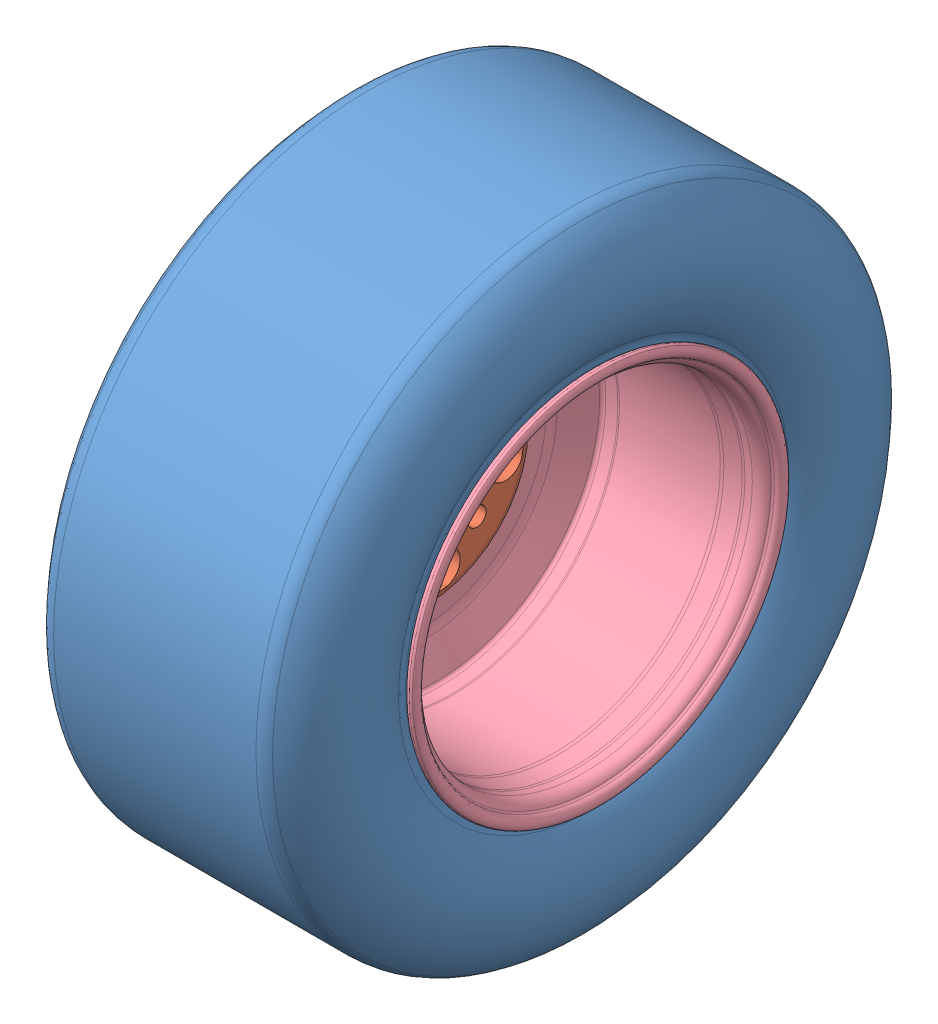
SolidWorks assembly FS2-WT-A-0002-V1, REAR TIRE, configuration Default. Lengths in mm.
Overall size (205.74 459.74 459.74).
4 component instances, 4 part files, 7 mates.
Components (placement in the parent):
- TYRE, 18.0X 6.0-10 R25B C2000, H43101R25B, Hoozier-1: TYRE, 18.0X 6.0-10 R25B C2000, H43101R25B, Hoozier [7] at origin size (205.74 459.74 459.74)
- WHEEL, 10i Center, Keizer-1: WHEEL, 10i Center, Keizer [Default] at (-49.403 0 0) x (0 0 1) z (-1 0 0) size (187.33 187.33 20.83)
- WHEEL, OUTER HALF 10x2 10i, Keizer-1: WHEEL, OUTER HALF 10x2 10i, Keizer [Default] at (-38.608 0 0) x (0 0 1) z (-1 0 0) size (276.85 276.85 58.63)
- WHEEL, INNER HALF 10x5BC 10i, Keizer-2: WHEEL, INNER HALF 10x5BC 10i, Keizer [Default] at (-38.608 0 0) x (0 0 -1) z (1 0 0) size (276.85 276.85 137.37)
Mates (geometry in assembly coordinates):
- Coincident2: coincident: point of TYRE, 18.0X 6.0-10 R25B C2000, H43101R25B, Hoozier-1
- Coincident3: coincident anti-aligned: plane of TYRE, 18.0X 6.0-10 R25B C2000, H43101R25B, Hoozier-1 through (-88.9 0 0) normal (-1 0 0); circle of WHEEL, OUTER HALF 10x2 10i, Keizer-1
- Concentric1: concentric aligned: cylinder of TYRE, 18.0X 6.0-10 R25B C2000, H43101R25B, Hoozier-1 through (0 0 0) axis (1 0 0) radius 229.87; cone of WHEEL, OUTER HALF 10x2 10i, Keizer-1 through (-70.3228 0 0) axis (1 0 0)
- Coincident4: coincident anti-aligned: plane of WHEEL, 10i Center, Keizer-1 through (-41.783 -94.7864 -94.7864) normal (1 0 0); plane of WHEEL, OUTER HALF 10x2 10i, Keizer-1 through (-41.783 0 0) normal (-1 0 0)
- Concentric2: concentric anti-aligned: cylinder of TYRE, 18.0X 6.0-10 R25B C2000, H43101R25B, Hoozier-1 through (0 0 0) axis (1 0 0) radius 229.87; cylinder of WHEEL, 10i Center, Keizer-1 through (-41.783 0 0) axis (-1 0 0) radius 93.6625
- Coincident7: coincident anti-aligned: plane of WHEEL, OUTER HALF 10x2 10i, Keizer-1 through (-38.608 0 0) normal (1 0 0); plane of WHEEL, INNER HALF 10x5BC 10i, Keizer-2 through (-38.608 0 0) normal (-1 0 0)
- Concentric5: concentric aligned: cylinder of WHEEL, 10i Center, Keizer-1 through (-34.7504 0 0) axis (-1 0 0) radius 75.8825; cylinder of WHEEL, INNER HALF 10x5BC 10i, Keizer-2 through (98.7662 0 0) axis (-1 0 0) radius 76.2
